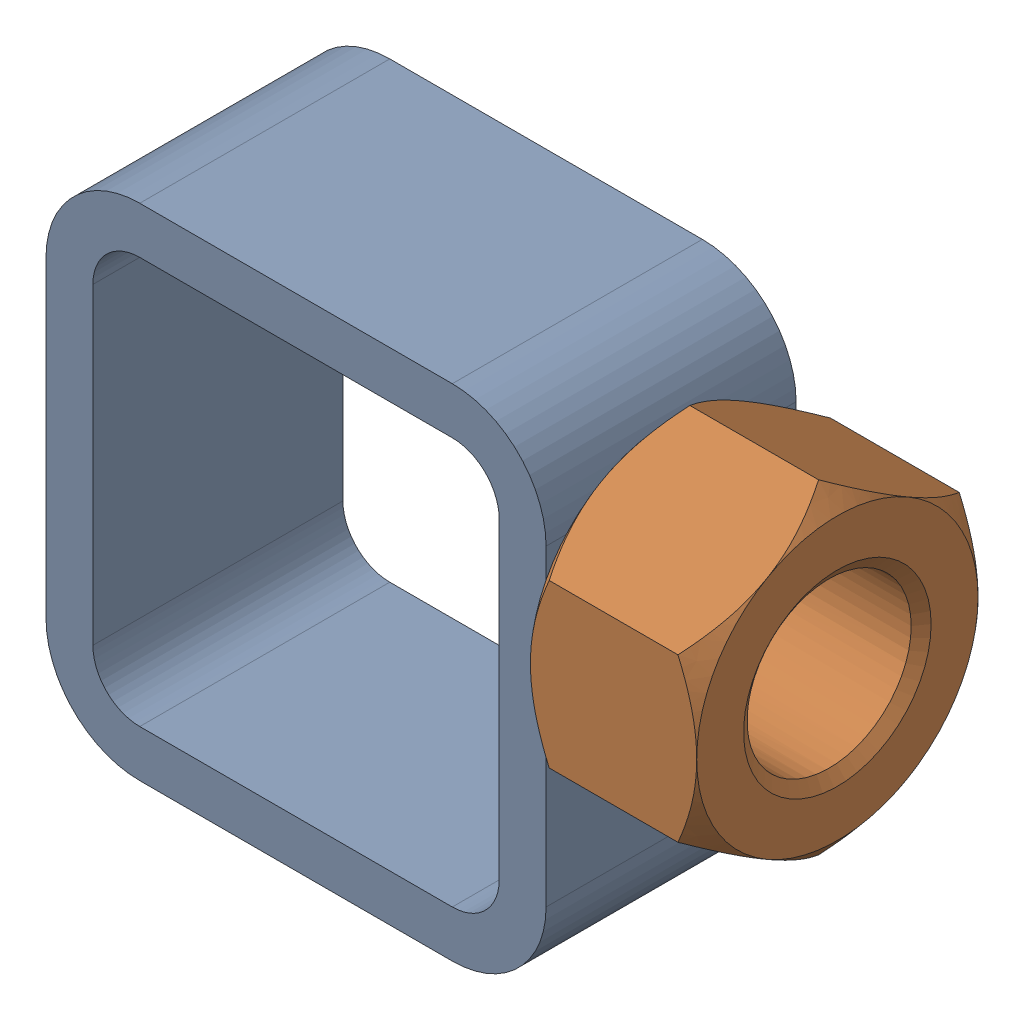
SolidWorks assembly 01-005-00-0-12, configuration Default. Lengths in mm.
Overall size (67.69 50.8 28.57).
2 component instances, 2 part files, 0 mates.
Components (placement in the parent):
- tube square_ai(PreviewCfg)-1: tube square_ai(PreviewCfg) [Default] at origin size (50.8 50.8 25.4)
- hex nut_ai(HNUT 0.7500-10-D-C)-1: hex nut_ai(HNUT 0.7500-10-D-C) [Default] at (67.691 31.75 0) x (0 0 -1) z (1 0 0) size (28.57 33 16.89)
